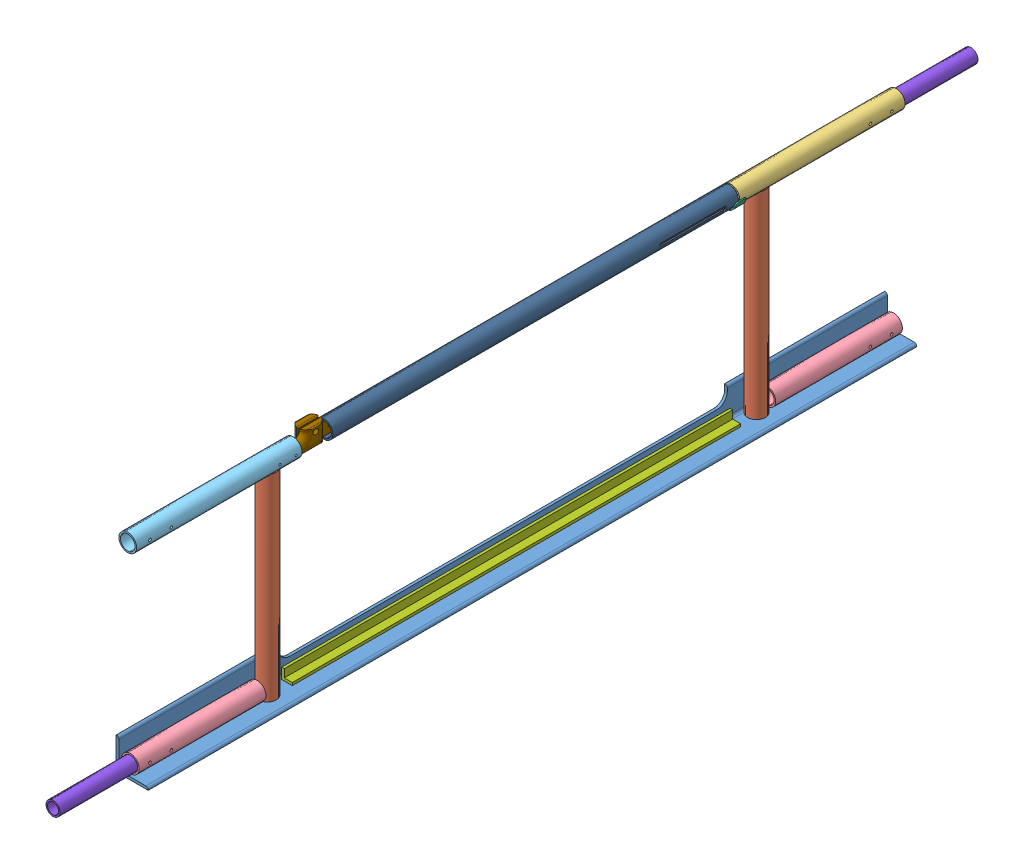
SolidWorks assembly FE-00029_ASM, configuration Default. Lengths in mm.
Overall size (76.2 519.84 2184.4).
16 component instances, 11 part files, 0 mates.
Components (placement in the parent):
- FE-00006_ASM-1: FE-00006_ASM [Default] at origin size (76.2 507.65 1828.8)
  - FE-00006-01-1: FE-00006-01 [Default] at origin size (76.2 76.2 1828.8)
  - FE-00006-10-1: FE-00006-10 [Default] at (27.432 6.35 1496.2188) size (42.16 471.23 42.16)
  - FE-00006-03-1: FE-00006-03 [Default] at (27.432 486.5688 393.7) x (1 0 0) z (0 0 -1) size (42.16 42.16 393.7)
  - FE-00006-02-1: FE-00006-02 [Default] at (27.432 27.432 1520.825) size (42.16 42.16 301.62)
  - FE-00006-02-2: FE-00006-02 [Default] at (27.432 27.432 307.975) x (1 0 0) z (0 0 -1) size (42.16 42.16 301.62)
  - FE-00006-10-2: FE-00006-10 [Default] at (27.432 6.35 332.5876) size (42.16 471.23 42.16)
  - FE-00006-05-1: FE-00006-05 [Default] at (27.432 486.5688 1435.1) size (42.16 42.16 393.7)
  - FE-00006-08-1: FE-00006-08 [Default] at (27.432 486.5688 381) size (48.26 22.22 25.4)
  - FE-00006-09-1: FE-00006-09 [Default] at (12.7 6.35 381) size (25.4 25.4 1066.8)
- FE-00026-1: FE-00026 [Default] at (27.432 27.432 1651) size (33.4 33.4 355.6)
- FE-00026-2: FE-00026 [Default] at (27.432 486.5688 177.8) x (1 0 0) z (0 0 -1) size (33.4 33.4 355.6)
- FE-00027-1: FE-00027 [Default] at (29.0202 469.0397 1500.1875) x (1 0.000041 0) z (0 0.000003 1) size (15.88 50.56 126.92)
- FE-00027-2: FE-00027 [Default] at (25.8452 469.039 1296.9875) x (-1 -0.000041 0) z (0 -0.000003 -1) size (15.88 50.56 126.92)
- FE-00028-1: FE-00028 [Default] at (27.432 486.5728 879.1575) x (0 -0.000003 -1) z (1 0.000041 0) size (965.2 42.16 42.16)
- FE-00031-1: FE-00031 [Default] at (27.432 486.5717 428.3075) x (0 0.000003 1) z (-1 -0.000041 0) size (304.8 33.4 33.4)
